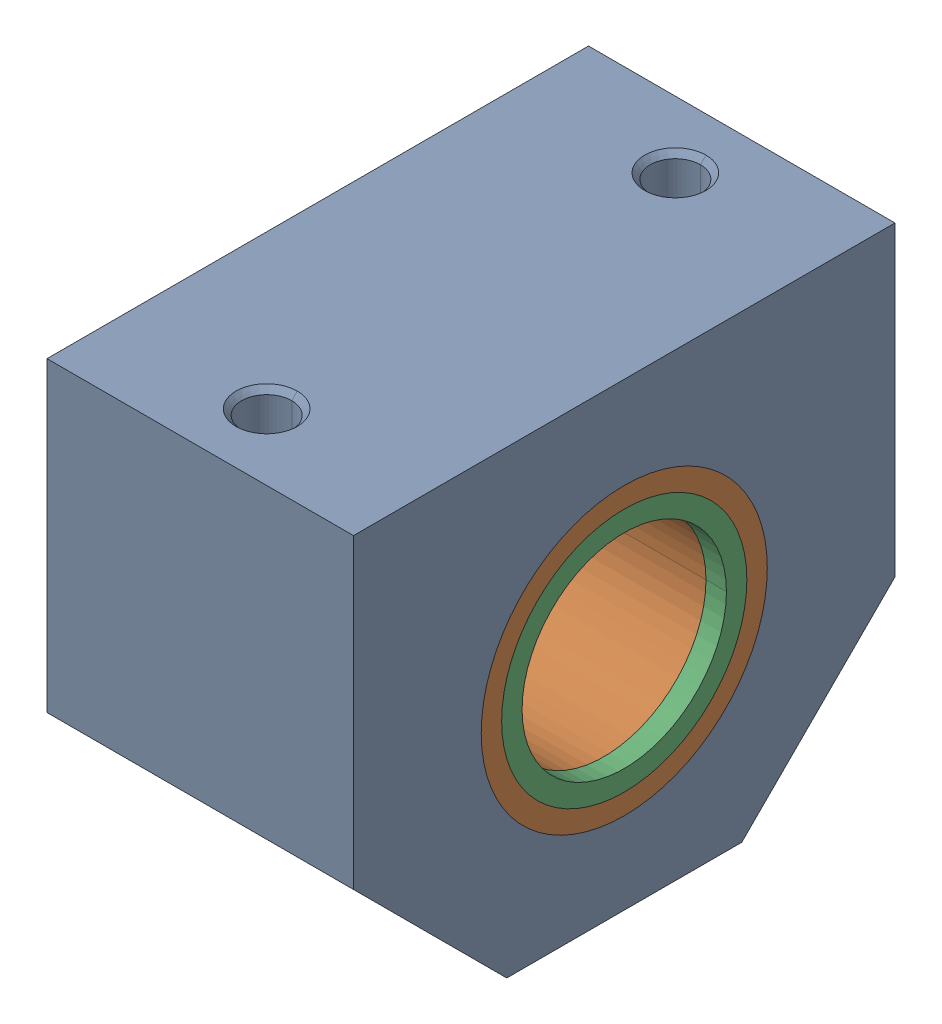
SolidWorks assembly LUHR_20, configuration Default. Lengths in mm.
Overall size (30 45 53).
4 component instances, 3 part files, 0 mates.
Components (placement in the parent):
- _LUHR20_b_2-1: _LUHR20_b_2 [Default] at origin size (30 45 53)
- _LBBR20_b_4-1: _LBBR20_b_4 [Default] x (-1 0 0) z (0 0 1) size (30 28 28.04)
- _LBBR20_ls_6-1: _LBBR20_ls_6 [Default] at (15 0 0) x (-1 0 0) z (0 0 1) size (2 24 24)
- _LBBR20_ls_6-2: _LBBR20_ls_6 [Default] at (-15 0 0) size (2 24 24)
